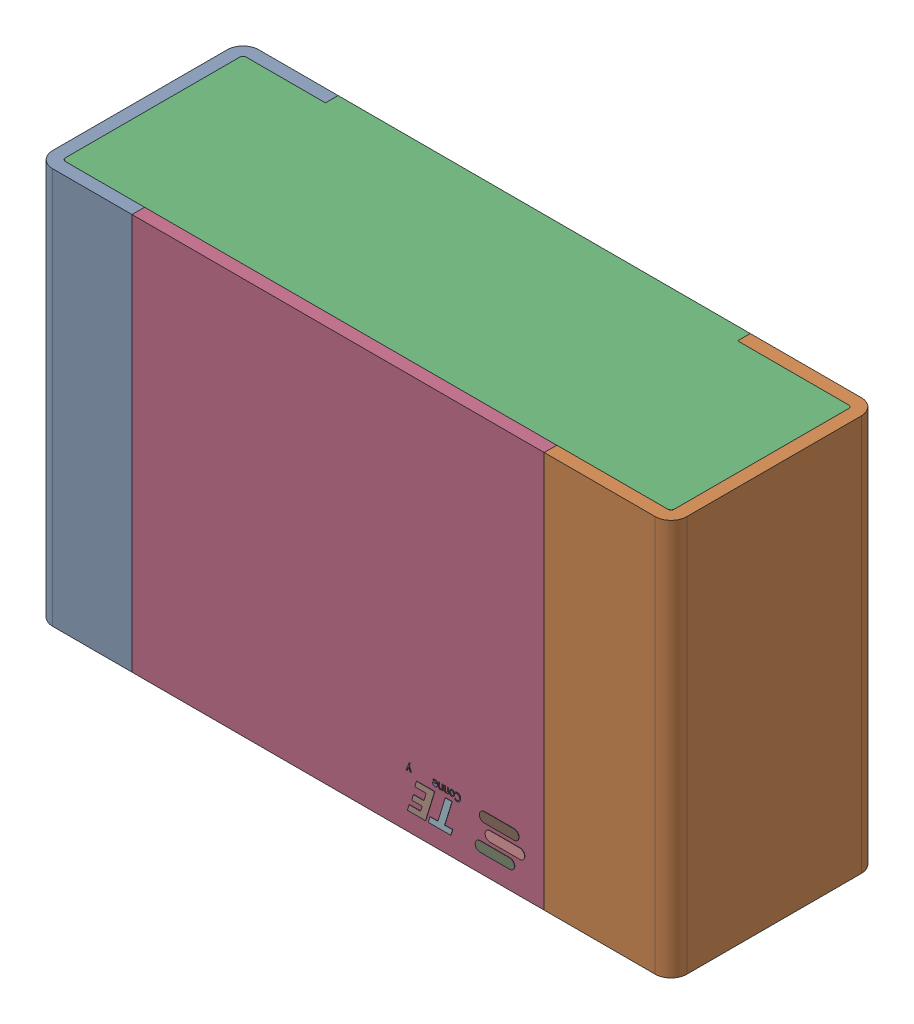
SolidWorks assembly RLL1.step, configuration Default. Lengths in mm.
Overall size (2 1.25 0.65).
5 component instances, 4 part files, 0 mates.
Components (placement in the parent):
- Res_TE_Connectivity_CPF0805B66R5E1_eec.step-1: Res_TE_Connectivity_CPF0805B66R5E1_eec.step [Default] at (10.287 31.181 0) x (-1 0 0) z (0 0 1) size (2 1.25 0.65)
  - 1.step-1: 1.step [Default] at origin size (2 1.25 0.65)
  - 2.step-1: 2.step [Default] at origin size (1.92 1.25 0.61)
  - 3.step-1: 3.step [Default] at origin size (1.3 1.25 0.04)
  - TE connectivity Logo 1 (2).step-1: TE connectivity Logo 1 (2).step [Default] at (5.4285 0.313 0.551) x (-1 0 0) z (0 0 1) size (0.37 0.13 0.11)
